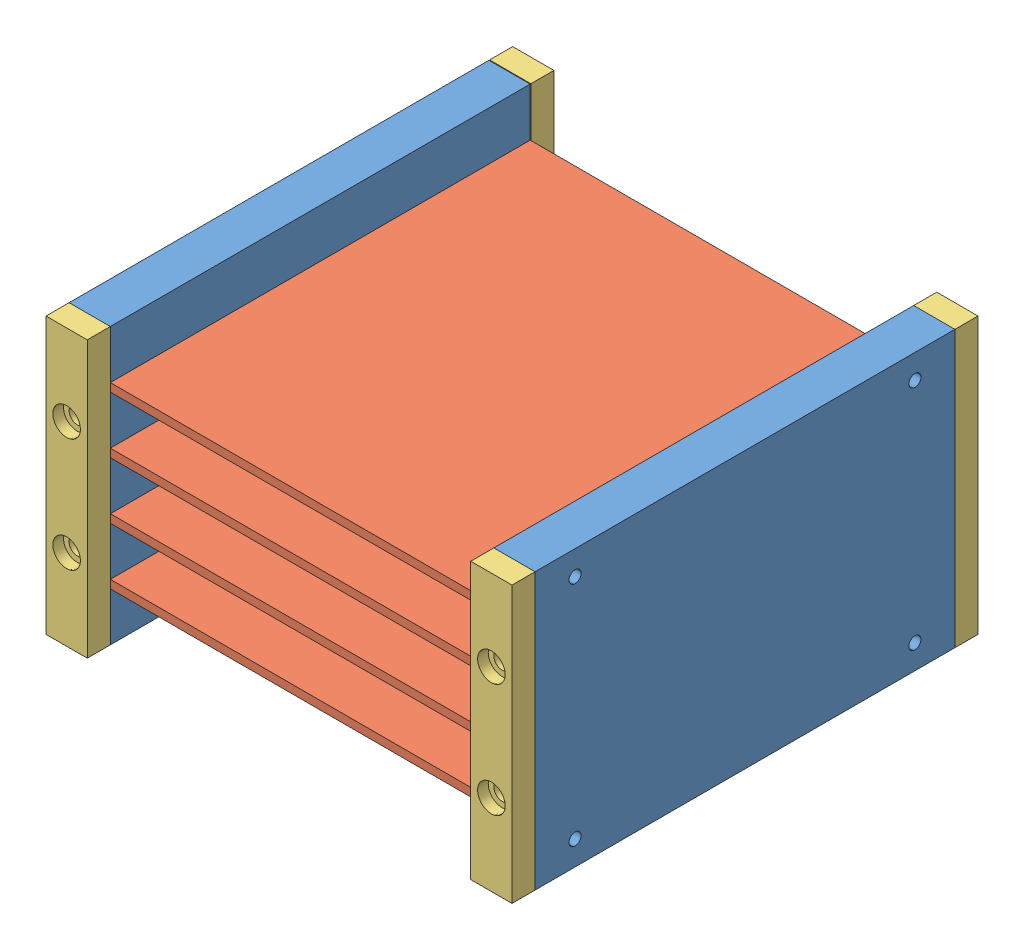
SolidWorks assembly STACK_SHELVES, configuration Default. Lengths in mm.
Overall size (96 56.8 96.14).
10 component instances, 3 part files, 28 mates.
Components (placement in the parent):
- PCB_SHELF-1: PCB_SHELF [Default] at (9.1658 22.2347 29.3721) size (8.5 56.8 86.5)
- FAKE_PCB-1: FAKE_PCB [Default] at (11.6658 67.3347 115.8721) size (91 1.7 86.5)
- FAKE_PCB-2: FAKE_PCB [Default] at (11.6658 55.6347 115.8721) size (91 1.7 86.5)
- FAKE_PCB-3: FAKE_PCB [Default] at (11.6658 43.9347 115.8721) size (91 1.7 86.5)
- FAKE_PCB-4: FAKE_PCB [Default] at (11.6658 32.2347 115.8721) size (91 1.7 86.5)
- PCB_SHELF-2: PCB_SHELF [Default] at (105.1658 22.2347 115.8721) x (-1 0 0) z (0 0 -1) size (8.5 56.8 86.5)
- PCB_SHELF_ENDS-1: PCB_SHELF_ENDS [Default] at (9.1658 79.0347 115.8721) size (8.5 56.8 4.75)
- PCB_SHELF_ENDS-2: PCB_SHELF_ENDS [Default] at (17.6658 79.0347 29.2356) x (-1 0 0) z (0 0 -1) size (8.5 56.8 4.75)
- PCB_SHELF_ENDS-3: PCB_SHELF_ENDS [Default] at (96.6658 79.0347 115.8721) size (8.5 56.8 4.75)
- PCB_SHELF_ENDS-4: PCB_SHELF_ENDS [Default] at (105.1658 79.0347 29.3721) x (-1 0 0) z (0 0 -1) size (8.5 56.8 4.75)
Mates (geometry in assembly coordinates):
- Coincident1: coincident anti-aligned: plane of PCB_SHELF-1 through (11.6658 69.0347 115.8721) normal (1 0 0); plane of FAKE_PCB-1 through (11.6658 69.0347 115.8721) normal (-1 0 0)
- Parallel1: parallel anti-aligned: plane of PCB_SHELF-1 through (11.6658 67.3347 115.8721) normal (0 1 0); plane of FAKE_PCB-1 through (11.6658 67.3347 115.8721) normal (0 -1 0)
- Coincident4: coincident aligned: plane of PCB_SHELF-1 through (9.1658 22.2347 115.8721) normal (0 0 1); plane of FAKE_PCB-1 through (102.6658 69.0347 115.8721) normal (0 0 1)
- Coincident5: coincident anti-aligned: plane of PCB_SHELF-1 through (11.6658 67.3347 115.8721) normal (0 1 0); plane of FAKE_PCB-1 through (11.6658 67.3347 115.8721) normal (0 -1 0)
- Coincident6: coincident anti-aligned: plane of PCB_SHELF-1 through (11.6658 57.3347 115.8721) normal (1 0 0); plane of FAKE_PCB-2 through (11.6658 57.3347 115.8721) normal (-1 0 0)
- Coincident7: coincident anti-aligned: plane of PCB_SHELF-1 through (17.6658 57.3347 115.8721) normal (0 -1 0); plane of FAKE_PCB-2 through (11.6658 57.3347 115.8721) normal (0 1 0)
- Coincident8: coincident aligned: plane of PCB_SHELF-1 through (9.1658 22.2347 115.8721) normal (0 0 1); plane of FAKE_PCB-2 through (102.6658 57.3347 115.8721) normal (0 0 1)
- Coincident9: coincident anti-aligned: plane of PCB_SHELF-1 through (11.6658 45.6347 115.8721) normal (1 0 0); plane of FAKE_PCB-3 through (11.6658 45.6347 115.8721) normal (-1 0 0)
- Coincident10: coincident anti-aligned: plane of PCB_SHELF-1 through (17.6658 45.6347 115.8721) normal (0 -1 0); plane of FAKE_PCB-3 through (11.6658 45.6347 115.8721) normal (0 1 0)
- Coincident11: coincident aligned: plane of PCB_SHELF-1 through (9.1658 22.2347 115.8721) normal (0 0 1); plane of FAKE_PCB-3 through (102.6658 45.6347 115.8721) normal (0 0 1)
- Coincident12: coincident anti-aligned: plane of PCB_SHELF-1 through (11.6658 33.9347 115.8721) normal (1 0 0); plane of FAKE_PCB-4 through (11.6658 33.9347 115.8721) normal (-1 0 0)
- Coincident13: coincident anti-aligned: plane of PCB_SHELF-1 through (17.6658 33.9347 115.8721) normal (0 -1 0); plane of FAKE_PCB-4 through (11.6658 33.9347 115.8721) normal (0 1 0)
- Coincident14: coincident aligned: plane of PCB_SHELF-1 through (9.1658 22.2347 115.8721) normal (0 0 1); plane of FAKE_PCB-4 through (102.6658 33.9347 115.8721) normal (0 0 1)
- Coincident15: coincident anti-aligned: plane of FAKE_PCB-4 through (102.6658 33.9347 29.3721) normal (1 0 0); plane of PCB_SHELF-2 through (102.6658 33.9347 29.3721) normal (-1 0 0)
- Coincident16: coincident anti-aligned: plane of FAKE_PCB-4 through (11.6658 33.9347 115.8721) normal (0 1 0); plane of PCB_SHELF-2 through (96.6658 33.9347 29.3721) normal (0 -1 0)
- Coincident17: coincident aligned: plane of FAKE_PCB-4 through (102.6658 33.9347 115.8721) normal (0 0 1); plane of PCB_SHELF-2 through (105.1658 22.2347 115.8721) normal (0 0 1)
- Coincident18: coincident aligned: plane of FAKE_PCB-3 through (102.6658 45.6347 115.8721) normal (0 0 1); plane of PCB_SHELF-2 through (105.1658 22.2347 115.8721) normal (0 0 1)
- Coincident19: coincident aligned: plane of FAKE_PCB-2 through (102.6658 57.3347 115.8721) normal (0 0 1); plane of PCB_SHELF-2 through (105.1658 22.2347 115.8721) normal (0 0 1)
- Coincident20: coincident aligned: plane of FAKE_PCB-1 through (102.6658 69.0347 115.8721) normal (0 0 1); plane of PCB_SHELF-2 through (105.1658 22.2347 115.8721) normal (0 0 1)
- Coincident21: coincident aligned: circle of PCB_SHELF-2; circle of PCB_SHELF_ENDS-3
- Coincident22: coincident aligned: circle of PCB_SHELF-2; circle of PCB_SHELF_ENDS-3
- Coincident23: coincident aligned: circle of PCB_SHELF-1; circle of PCB_SHELF_ENDS-1
- Coincident24: coincident aligned: circle of PCB_SHELF-1; circle of PCB_SHELF_ENDS-1
- Concentric1: concentric aligned: circle of PCB_SHELF-2; circle of PCB_SHELF_ENDS-4
- Concentric2: concentric aligned: circle of PCB_SHELF-2; circle of PCB_SHELF_ENDS-4
- Coincident25: coincident anti-aligned: plane of PCB_SHELF-2 through (105.1658 22.2347 29.3721) normal (0 0 -1); plane of PCB_SHELF_ENDS-4 through (105.1658 79.0347 29.3721) normal (0 0 1)
- Concentric3: concentric aligned: circle of PCB_SHELF-1; circle of PCB_SHELF_ENDS-2
- Concentric4: concentric aligned: circle of PCB_SHELF-1; circle of PCB_SHELF_ENDS-2
